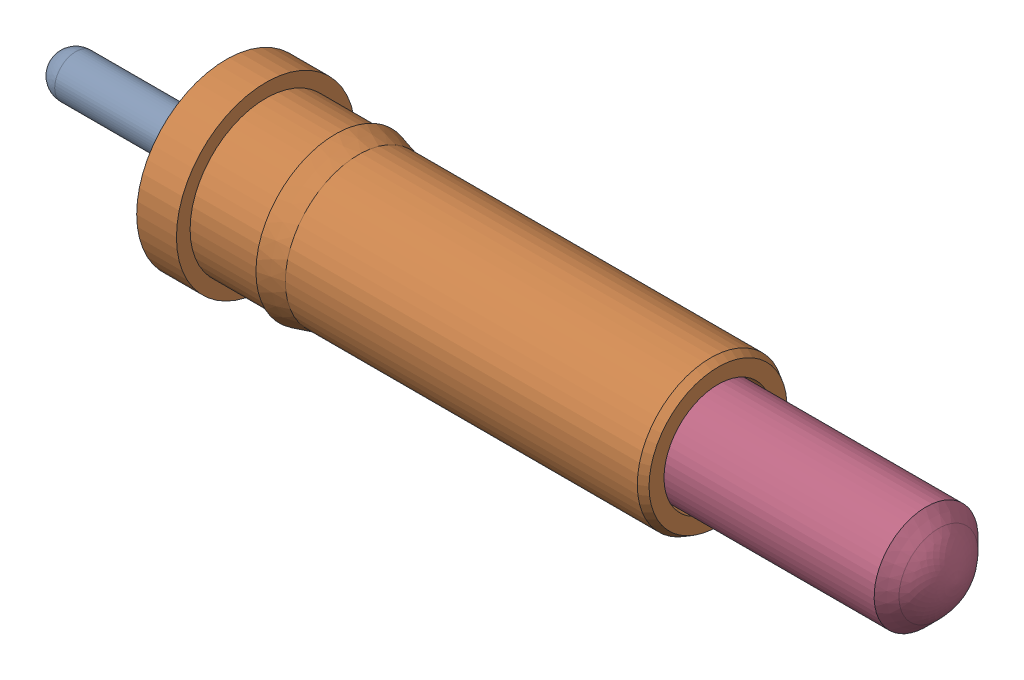
SolidWorks assembly mill-max-0908-2-15-20-75-14-11-0_1_2, configuration Default. Lengths in mm.
Overall size (9.22 1.83 1.83).
4 component instances, 4 part files, 0 mates.
Components (placement in the parent):
- mill-max-0908-2-15-20-75-14-11-0_0963-0_0963-0-00-20-00-00-13-0_1-1: mill-max-0908-2-15-20-75-14-11-0_0963-0_0963-0-00-20-00-00-13-0_1 [Default] at (0.1795 -0.8235 -1.1087) size (4.04 1.31 1.31)
- mill-max-0908-2-15-20-75-14-11-0_0954-0_0954-0-00-20-00-00-13-0_1-1: mill-max-0908-2-15-20-75-14-11-0_0954-0_0954-0-00-20-00-00-13-0_1 [Default] at (1.9321 -0.8235 -1.1087) size (5.03 1.83 1.83)
- mill-max-0908-2-15-20-75-14-11-0_SPRING_0975-0-00-00-75-14-45-0_1-1: mill-max-0908-2-15-20-75-14-11-0_SPRING_0975-0-00-00-75-14-45-0_1 [Default] at (5.5978 -0.8235 -1.1087) x (0 -0.998082 0.061903) z (-1 0 0) size (0.8 0.8 3.43)
- mill-max-0908-2-15-20-75-14-11-0_0918-X_0918-7-00-20-00-00-13-0_1-1: mill-max-0908-2-15-20-75-14-11-0_0918-X_0918-7-00-20-00-00-13-0_1 [Default] at (3.9133 -0.8235 -1.1087) x (1 0 0) z (0 0.540629 0.841261) size (5.49 1.25 1.25)
